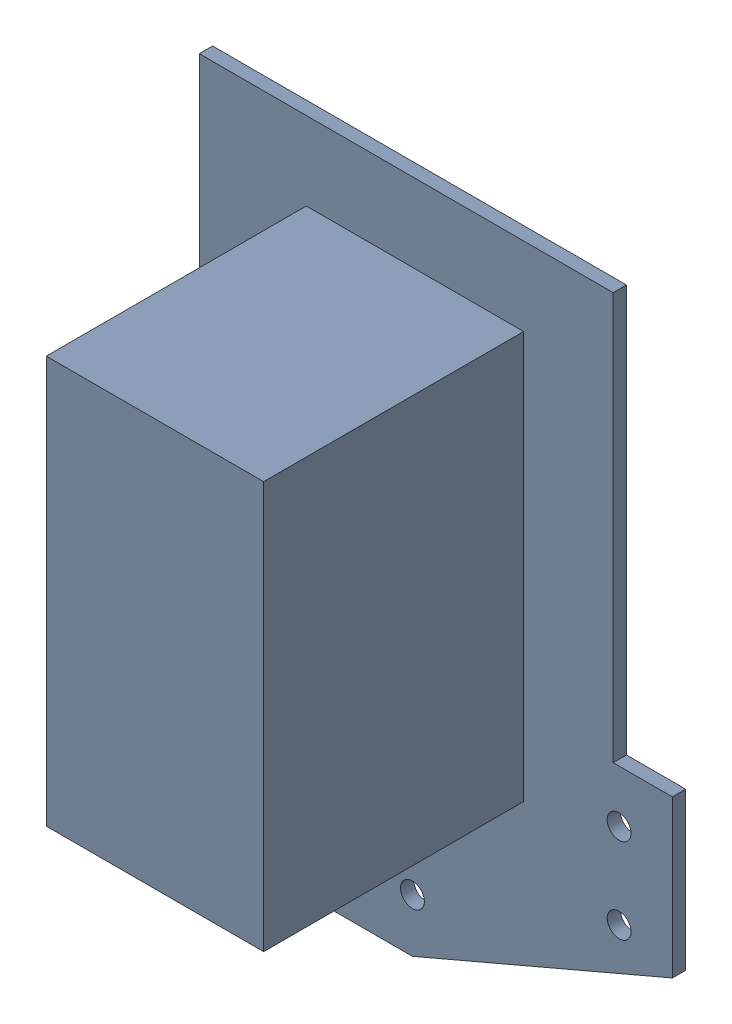
SolidWorks assembly gripper_grip_link, configuration Default. Lengths in mm.
Overall size (56.39 80.47 67.37).
2 component instances, 2 part files, 4 mates.
Components (placement in the parent):
- gripper_roll_link-1: gripper_roll_link [Default] at (0 -18.034 9.8425) x (0 1 0) z (1 0 0) size (80.47 67.37 56.39)
- gripper_gear_cover-1: gripper_gear_cover [Default] at (52.7817 25.4 -15.0245) x (0 -1 0) z (0.999848 0 -0.017452) (suppressed, hidden)
Mates (geometry in assembly coordinates):
- Coincident3: coordinate: point of gripper_roll_link-1; point of assembly
- Concentric1: concentric aligned: cylinder of gripper_roll_link-1 through (4.7625 18.034 -18.27) axis (0 1 0) radius 1.4224; cylinder of gripper_gear_cover-1 through (4.7625 16.4465 -18.27) axis (0 1 0) radius 1.4224
- Coincident4: coincident anti-aligned: plane of gripper_roll_link-1 through (7.9375 16.4465 0.6985) normal (0 -1 0); plane of gripper_gear_cover-1 through (24.1833 16.4465 -16.1131) normal (0 1 0)
- Angle1: planar angle = 1.553343 rad aligned: plane of gripper_gear_cover-1 through (24.211 25.4 -14.5258) normal (0.017452 0 0.999848); plane of gripper_roll_link-1 through (1.5875 18.034 -11.43) normal (1 0 0)
